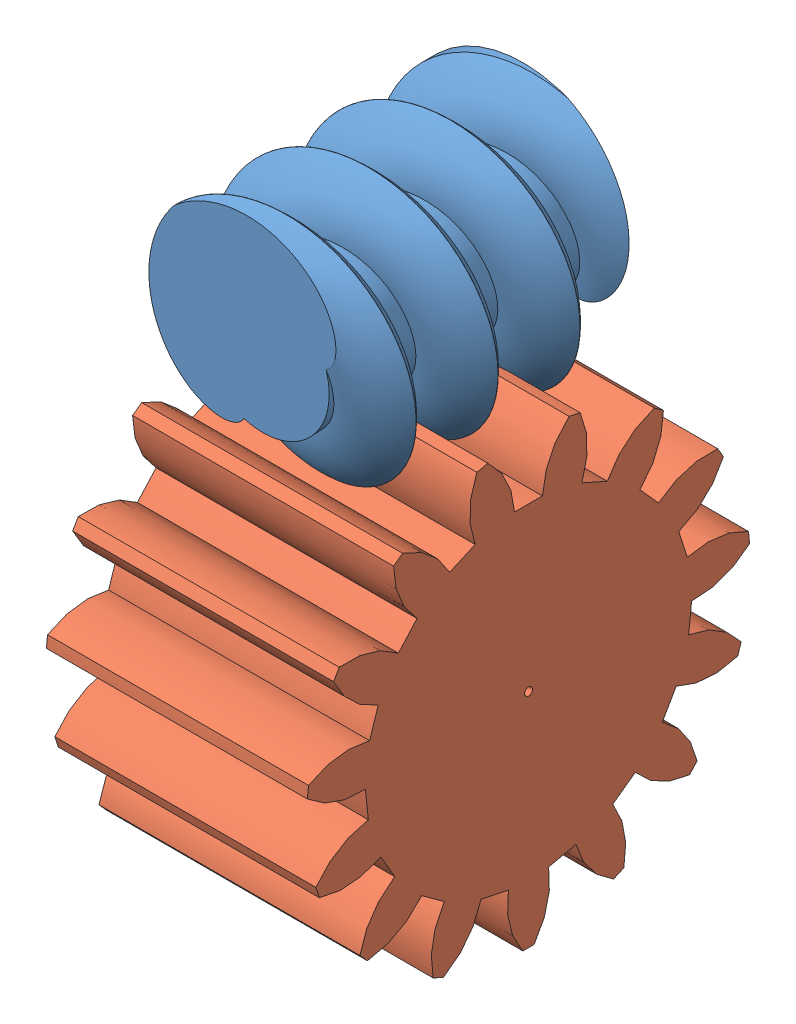
SolidWorks assembly worm and racl, configuration Default. Lengths in mm.
Overall size (25.4 62.54 43.04).
2 component instances, 2 part files, 1 mates.
Components (placement in the parent):
- WormGear-1: WormGear [Default] at (-19.2889 73.2787 -1.4298) size (24.47 24.46 31.17)
- spur gear_ai-2: spur gear_ai [Inch - Spur gear 10DP 15T 20PA 0.5FW ---S15N3.0H2.0L0.03125N] at (-32.0389 44.5767 -2.0061) size (25.4 42.82 43.04)
Mates (geometry in assembly coordinates):
- Distance11: distance = 28.702 mm aligned: plane of spur gear_ai-2 through (-32.0389 44.5767 -2.0061) normal (0 1 0); plane of WormGear-1 through (-19.2889 73.2787 -1.4298) normal (0 1 0)
